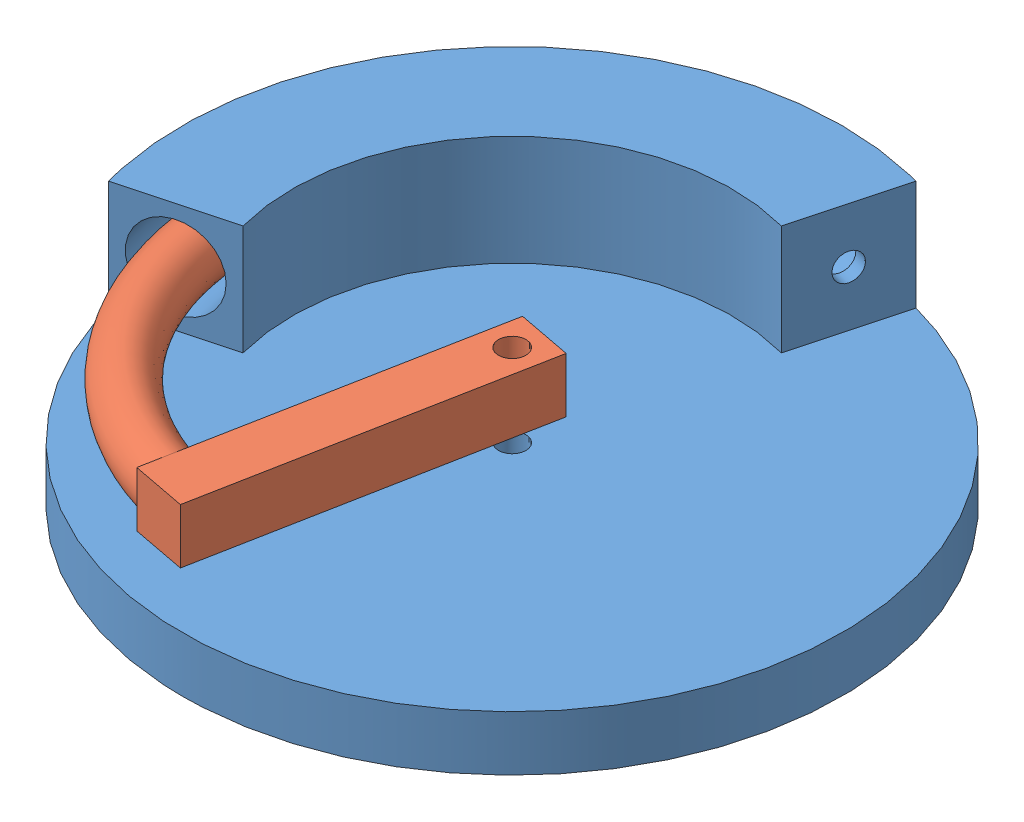
SolidWorks assembly Rotational_Hydraulic_Actuator_Assembly_v1_0_0, configuration Default. Lengths in mm.
Overall size (85.78 19.05 80.26).
2 component instances, 2 part files, 3 mates.
Components (placement in the parent):
- Cylinder_and_Base-1: Cylinder_and_Base [Default] at origin size (76.2 19.05 76.2)
- Piston_and_Rod-1: Piston_and_Rod [Default] at (0 12.7 0) x (0.89363 0 -0.448804) z (0.448804 0 0.89363) size (39.38 9.9 66.34)
Mates (geometry in assembly coordinates):
- Concentric3: concentric aligned: cylinder of Cylinder_and_Base-1 through (0 -0.001 0) axis (0 1 0) radius 1.5875; cylinder of Piston_and_Rod-1 through (0 7.7465 0) axis (0 1 0) radius 1.5875
- LimitAngle2: limit planar angle = 1.119925 rad anti-aligned: plane of Cylinder_and_Base-1 through (0 19.05 0) normal (0.258819 0 0.965926); plane of Piston_and_Rod-1 through (-3.1184 12.7 -0.5967) normal (-0.982179 0 -0.187947)
- Coincident1: coincident aligned: plane of Piston_and_Rod-1 through (0 12.7 0) normal (0 1 0)
